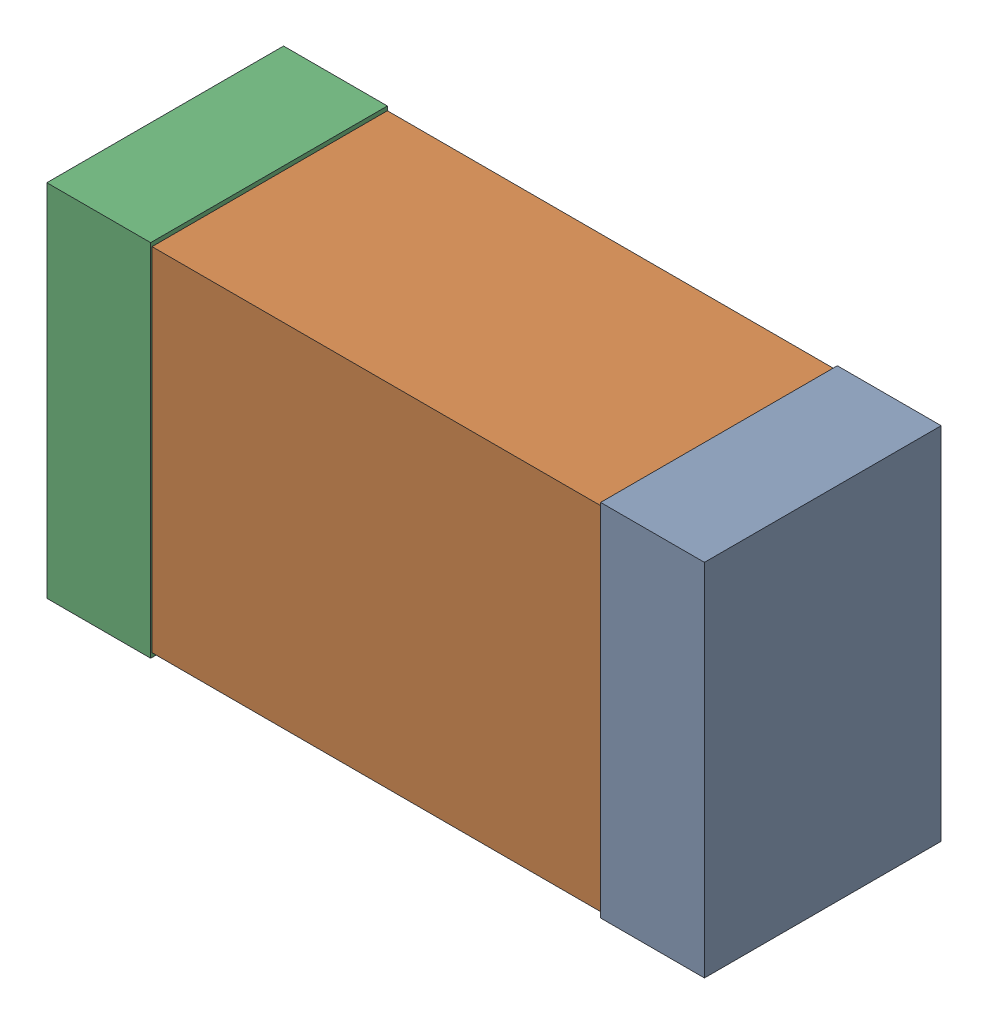
SolidWorks assembly R8Kanaloa_v2.0.0_GPIO_b, configuration Default. Lengths in mm.
Overall size (2.38 1.3 0.85).
6 component instances, 2 part files, 0 mates.
Components (placement in the parent):
- 352877648-1: 352877648 [Default] at (123.936 123.444 0) size (0.38 1.3 0.85)
  - Extruded_14-1: Extruded_14 [Default] at origin size (0.38 1.3 0.85)
- 352877904-1: 352877904 [Default] at (122.936 123.444 0) size (2.2 1.27 0.85)
  - Extruded_18-1: Extruded_18 [Default] at origin size (2.2 1.27 0.85)
- 352877648-2: 352877648 [Default] at (121.936 123.444 0) size (0.38 1.3 0.85)
  - Extruded_14-1: Extruded_14 [Default] at origin size (0.38 1.3 0.85)
